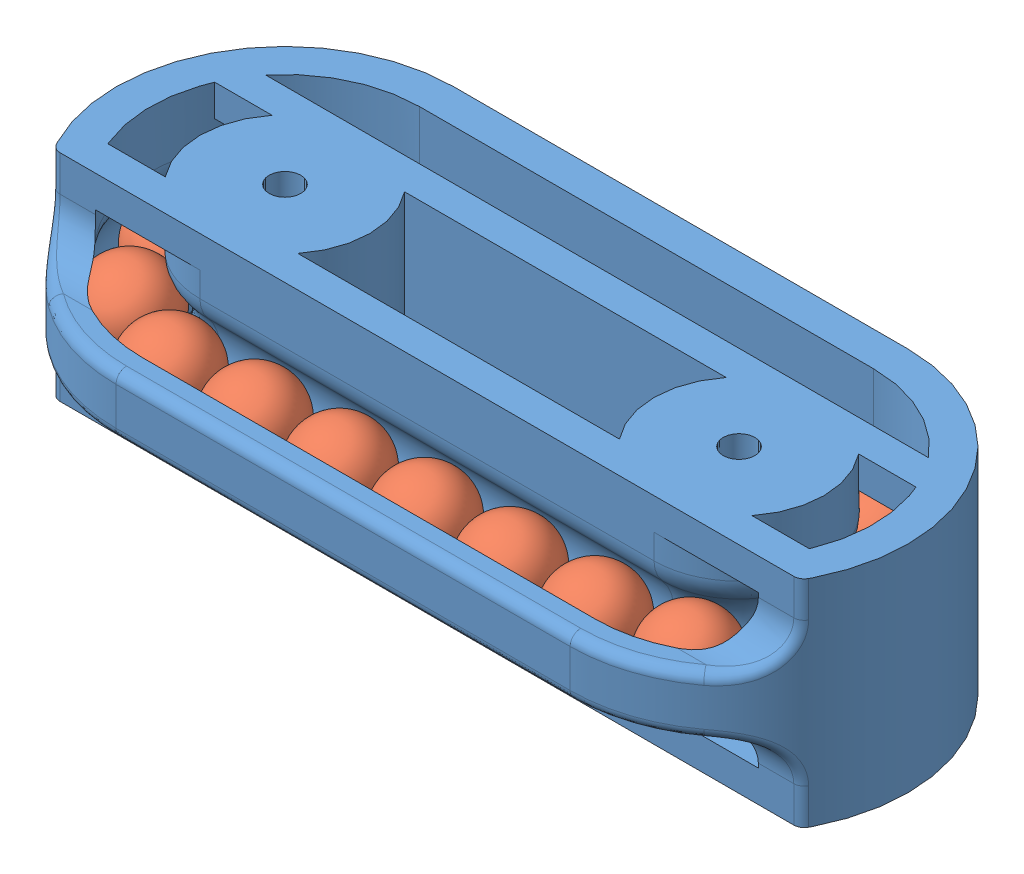
SolidWorks assembly loaded_bearing_body, configuration Default. Lengths in mm.
Overall size (75 20.4 32).
20 component instances, 2 part files, 1 mates.
Components (placement in the parent):
- bearing_body-2: bearing_body [Default] at origin size (75 20.4 32)
- delrin_ball_5-16_inch-20: delrin_ball_5-16_inch [Default] at (-21.5 0 -10.4333) size (7.94 7.94 7.94)
- delrin_ball_5-16_inch-21: delrin_ball_5-16_inch [Default] at (-28.7803 0 -7.4723) size (7.94 7.94 7.94)
- delrin_ball_5-16_inch-22: delrin_ball_5-16_inch [Default] at (-31.9288 0 -0.2689) size (7.94 7.94 7.94)
- delrin_ball_5-16_inch-23: delrin_ball_5-16_inch [Default] at (-29.1561 0 7.0868) size (7.94 7.94 7.94)
- delrin_ball_5-16_inch-24: delrin_ball_5-16_inch [Default] at (-22.036 0 10.4195) size (7.94 7.94 7.94)
- delrin_ball_5-16_inch-25: delrin_ball_5-16_inch [Default] at (-13.9756 0 10.4333) size (7.94 7.94 7.94)
- delrin_ball_5-16_inch-26: delrin_ball_5-16_inch [Default] at (-5.9163 0 10.4333) size (7.94 7.94 7.94)
- delrin_ball_5-16_inch-27: delrin_ball_5-16_inch [Default] at (2.143 0 10.4333) size (7.94 7.94 7.94)
- delrin_ball_5-16_inch-28: delrin_ball_5-16_inch [Default] at (10.2043 0 10.4333) size (7.94 7.94 7.94)
- delrin_ball_5-16_inch-29: delrin_ball_5-16_inch [Default] at (18.2636 0 10.4333) size (7.94 7.94 7.94)
- delrin_ball_5-16_inch-30: delrin_ball_5-16_inch [Default] at (26.1539 0 9.3383) size (7.94 7.94 7.94)
- delrin_ball_5-16_inch-31: delrin_ball_5-16_inch [Default] at (31.3507 0 3.4405) size (7.94 7.94 7.94)
- delrin_ball_5-16_inch-32: delrin_ball_5-16_inch [Default] at (30.9555 0 -4.4119) size (7.94 7.94 7.94)
- delrin_ball_5-16_inch-33: delrin_ball_5-16_inch [Default] at (25.193 0 -9.7582) size (7.94 7.94 7.94)
- delrin_ball_5-16_inch-34: delrin_ball_5-16_inch [Default] at (17.215 0 -10.4333) size (7.94 7.94 7.94)
- delrin_ball_5-16_inch-35: delrin_ball_5-16_inch [Default] at (9.1557 0 -10.4333) size (7.94 7.94 7.94)
- delrin_ball_5-16_inch-36: delrin_ball_5-16_inch [Default] at (1.0944 0 -10.4333) size (7.94 7.94 7.94)
- delrin_ball_5-16_inch-37: delrin_ball_5-16_inch [Default] at (-6.9649 0 -10.4333) size (7.94 7.94 7.94)
- delrin_ball_5-16_inch-38: delrin_ball_5-16_inch [Default] at (-15.0243 0 -10.4333) size (7.94 7.94 7.94)
Mates (geometry in assembly coordinates):
- PathMate3: path: point of delrin_ball_5-16_inch-20; curve of assembly; curve of assembly
